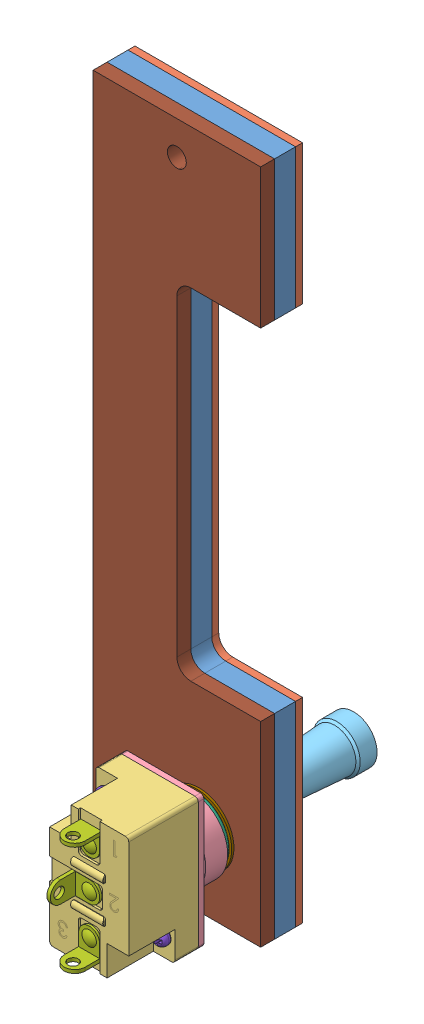
SolidWorks assembly DEFOG Panel, configuration Default. Lengths in mm.
Overall size (38.1 153.67 62.84).
16 component instances, 14 part files, 7 mates.
Components (placement in the parent):
- DEFOG Panel Lightplate-1: DEFOG Panel Lightplate [Default] at origin size (38.1 153.67 4.76)
- DEFOG Panel Legend Plate-1: DEFOG Panel Legend Plate [Default] at (0 0 -4.7625) x (-1 0 0) z (0 0 -1) size (38.1 153.67 1.59)
- SxAL-1: SxAL [S3AL - Conical Bat] at (-13.97 16.51 12.3952) x (-1 0 0) z (0 -1 0) size (18.01 62.84 30)
  - S2AL_SMC_body1-body-1: S2AL_SMC_body1-body [Default] at origin size (18.01 16.36 30)
  - S2AL_SMC_plate13-1: S2AL_SMC_plate13 [Default] at origin size (18.01 21.39 30)
  - S2AL_S2AL_bat-1: S2AL_S2AL_bat [Removed Bat] at (0 14.7066 0) size (7.39 24.87 7.39)
  - S2AL_AT537-1: S2AL_AT537 [Default] at (0 7.9629 0) x (1 0 0) z (0 -1 0) size (15.49 15.49 1.5)
  - S2AL_SMC_trmnls2-terminals-1: S2AL_SMC_trmnls2-terminals [Default] at (0 -15.0114 0) size (16.2 6.6 44.08)
  - S2AL_M2_5x7_5-1: S2AL_M2_5x7_5 [Default] at (6.4643 -5.2832 -10.541) x (1 0 0) z (0 -1 0) size (3.56 3.56 9.47)
  - S2AL_M2_5x7_5-2: S2AL_M2_5x7_5 [Default] at (-6.4643 -5.2832 10.541) x (1 0 0) z (0 -1 0) size (3.56 3.56 9.47)
  - S2AL_AT508-1: S2AL_AT508 [Default] at (0 8.9662 0) x (1 0 0) z (0 -1 0) size (15.8 15.8 0.51)
  - S2AL_AT503M-1: S2AL_AT503M [Default] at (0 12.0396 0) x (1 0 0) z (0 1 0) size (16 14 2.4)
  - Tall Locking Bat-1: Tall Locking Bat [Default] at origin (suppressed, hidden)
  - Conical Locking Bat-1: Conical Locking Bat [Default] x (0 0 -1) z (1 0 0) size (11.18 15.95 11.18)
  - Round Locking Bat-1: Round Locking Bat [Default] x (0 0 -1) z (1 0 0) (suppressed, hidden)
- DEFOG Panel Backplate-1: DEFOG Panel Backplate [Default] at origin size (38.1 153.67 3.17)
Mates (geometry in assembly coordinates):
- Concentric1: concentric aligned: cylinder of DEFOG Panel Legend Plate-1 through (-13.97 16.51 -6.35) axis (0 0 -1) radius 6.35; cylinder of SxAL-1/S2AL_SMC_plate13-1 through (-13.97 16.51 11.4554) axis (0 0 -1) radius 8.4963
- Parallel1: parallel aligned: plane of DEFOG Panel Lightplate-1 through (-38.1 153.67 -4.7625) normal (-1 0 0); plane of SxAL-1/S2AL_SMC_body1-body-1 through (-22.9743 2.2733 28.194) normal (-1 0 0)
- Distance2: distance = 3.175 mm anti-aligned: plane of DEFOG Panel Lightplate-1 through (-15.875 47.625 0) normal (0 0 1); plane of SxAL-1/S2AL_AT508-1 through (-13.97 16.51 3.175) normal (0 0 -1)
- InPlace1: in place: plane of ? through (-15.875 47.625 0) normal (0 0 1); plane of ? through (0 0 0) normal (0 0 1); moOrthogonalPlaneRef_w of ? through (-15.875 47.625 0) normal (0 0 1); plane of ? through (0 0 0) normal (0 1 0); plane of ? through (-15.875 47.625 0) normal (0 0 1); plane of ? through (0 0 0) normal (1 0 0); plane of ? through (-15.875 47.625 0) normal (0 0 1); unknown of ?
- Coincident1: coincident aligned: plane of DEFOG Panel Lightplate-1; plane of DEFOG Panel Backplate-1
- Coincident2: coincident aligned: moOrthogonalPlaneRef_w of DEFOG Panel Lightplate-1 through (0 0 0) normal (0 1 0); plane of DEFOG Panel Backplate-1 through (0 0 0) normal (0 1 0)
- Coincident3: coincident anti-aligned: moOrthogonalPlaneRef_w of DEFOG Panel Lightplate-1 through (0 0 0) normal (-1 0 0); plane of DEFOG Panel Backplate-1 through (0 0 0) normal (1 0 0)
